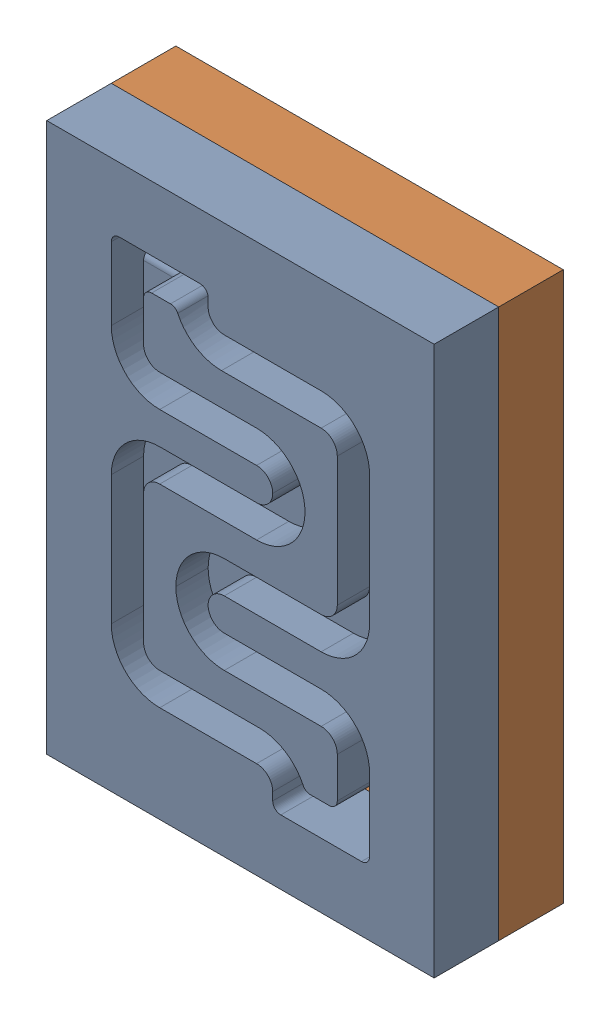
SolidWorks assembly square_small_comb_v3, configuration Default. Lengths in mm.
Overall size (12 17 4).
2 component instances, 2 part files, 3 mates.
Components (placement in the parent):
- square_small-3: square_small [Standard] at (-6.412 -9.5432 -7.709) x (1 0 0) z (0 -1 0) size (12 2 17)
- square small headplate-1: square small headplate [Standard] at (-6.412 -9.5432 -9.709) x (1 0 0) z (0 -1 0) size (12 2 17)
Mates (geometry in assembly coordinates):
- Deckungsgleich4: coincident: plane of square_small-3 through (-6.412 -9.5432 -7.709) normal (0 0 -1); plane of square small headplate-1 through (-6.412 -9.5432 -7.709) normal (0 0 1)
- Deckungsgleich6: coincident: plane of square_small-3 through (5.588 -9.5432 -5.709) normal (1 0 0); plane of square small headplate-1 through (5.588 -9.5432 -7.709) normal (1 0 0)
- Deckungsgleich7: coincident aligned: plane of square_small-3 through (-6.412 -9.5432 -5.709) normal (0 -1 0); plane of square small headplate-1 through (-6.412 -9.5432 -7.709) normal (0 -1 0)
